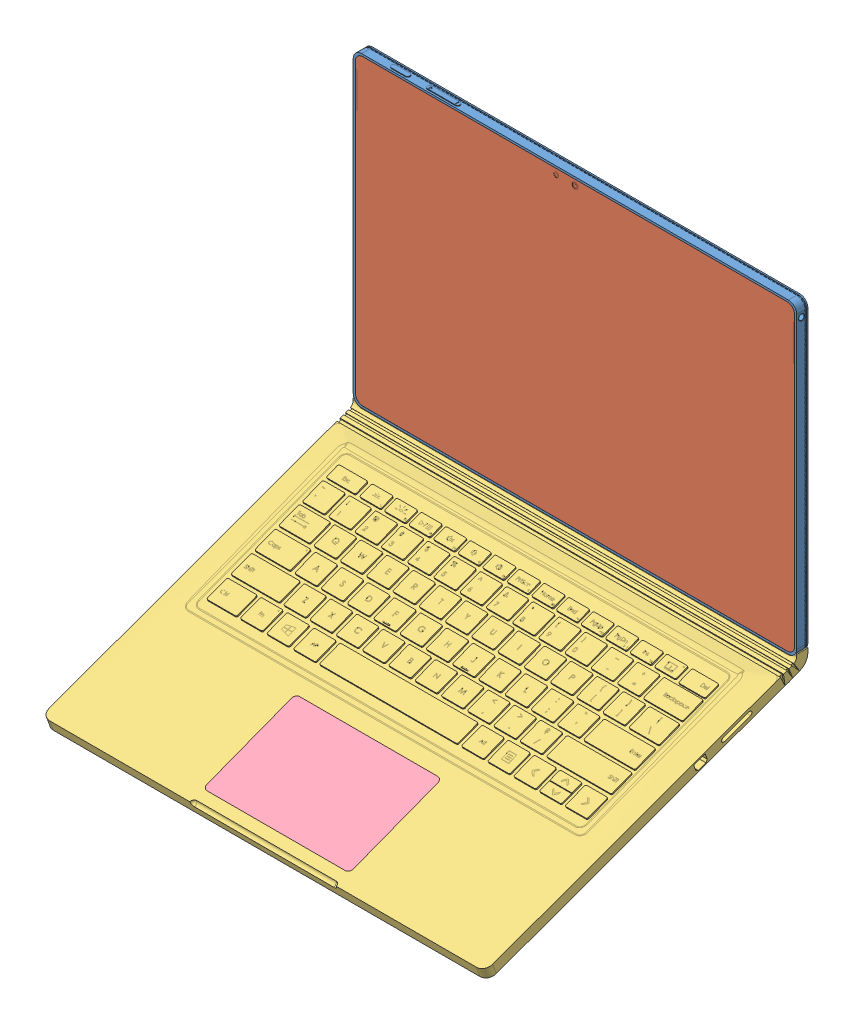
SolidWorks assembly Assem1, configuration Default. Lengths in mm.
Overall size (328.58 310.16 232.04).
4 component instances, 4 part files, 15 mates.
Components (placement in the parent):
- Monitor-1: Monitor [Default] at origin size (318 220.5 8.05)
- Display-1: Display [Default] at (0 0 7.5) size (326.85 238.53 0.46)
- Main Body-1: Main Body [Default] at origin size (318.39 103.66 231.99)
- Mouse Pad-1: Mouse Pad [Default] at (0 -91.311 -34.924) x (1 0 0) z (0 0.934014 0.357236) size (105 71 0.7)
Mates (geometry in assembly coordinates):
- Coincident1: coincident: plane of ? through (0 0 0) normal (0 0 1); plane of assembly through (0 0 0) normal (0 0 1)
- Coincident2: coincident: plane of ? through (0 0 0) normal (0 1 0); plane of assembly through (0 0 0) normal (0 1 0)
- Coincident3: coincident: plane of ? through (0 0 0) normal (1 0 0); plane of assembly through (0 0 0) normal (1 0 0)
- InPlace1: in place: plane of ? through (-152.1 -103.1 7.5) normal (0 0 1); plane of Display-1 through (0 0 7.5) normal (0 0 1); moOrthogonalPlaneRef_w of ? through (-152.1 -103.1 7.5) normal (0 0 1); plane of Display-1 through (0 0 7.5) normal (0 1 0); plane of ? through (-152.1 -103.1 7.5) normal (0 0 1); plane of Display-1 through (0 0 7.5) normal (1 0 0); plane of ? through (-152.1 -103.1 7.5) normal (0 0 1); unknown of Display-1
- Coincident4: coincident: plane of assembly; plane of assembly; plane of Monitor-1; plane of Display-1
- Coincident5: coincident: plane of ? through (0 0 7.5) normal (0 1 0); plane of Display-1 through (0 0 7.5) normal (0 1 0)
- Coincident6: coincident: plane of ? through (0 0 7.5) normal (-1 0 0); plane of Display-1 through (0 0 7.5) normal (1 0 0)
- InPlace2: in place: plane of ? through (0 0 0) normal (0 0 1); plane of ? through (0 0 0) normal (0 1 0); plane of ? through (0 0 0) normal (1 0 0); unknown of ?
- Coincident4: coincident: plane of assembly; plane of Main Body-1; plane of assembly
- Coincident5: coincident: plane of ? through (0 0 0) normal (0 1 0)
- Coincident6: coincident: plane of ? through (0 0 0) normal (1 0 0)
- InPlace3: in place: plane of ? through (49.5 -188.5119 219.2136) normal (0 0.934014 0.357236); plane of Mouse Pad-1 through (0 -91.311 -34.924) normal (0 0.934014 0.357236); plane of ? through (49.5 -188.5119 219.2136) normal (0 0.934014 0.357236); plane of Mouse Pad-1 through (0 -91.311 -34.924) normal (0 0.357236 -0.934014); plane of ? through (49.5 -188.5119 219.2136) normal (0 0.934014 0.357236); plane of Mouse Pad-1 through (0 -91.311 -34.924) normal (1 0 0); plane of ? through (49.5 -188.5119 219.2136) normal (0 0.934014 0.357236); unknown of Mouse Pad-1
- Coincident4: coincident: plane of assembly; plane of assembly; plane of Main Body-1; plane of Mouse Pad-1
- Coincident5: coincident: plane of ? through (0 -91.311 -34.924) normal (0 0.357236 -0.934014); plane of Mouse Pad-1 through (0 -91.311 -34.924) normal (0 0.357236 -0.934014)
- Coincident6: coincident: plane of ? through (0 -91.311 -34.924) normal (-1 0 0); plane of Mouse Pad-1 through (0 -91.311 -34.924) normal (1 0 0)
